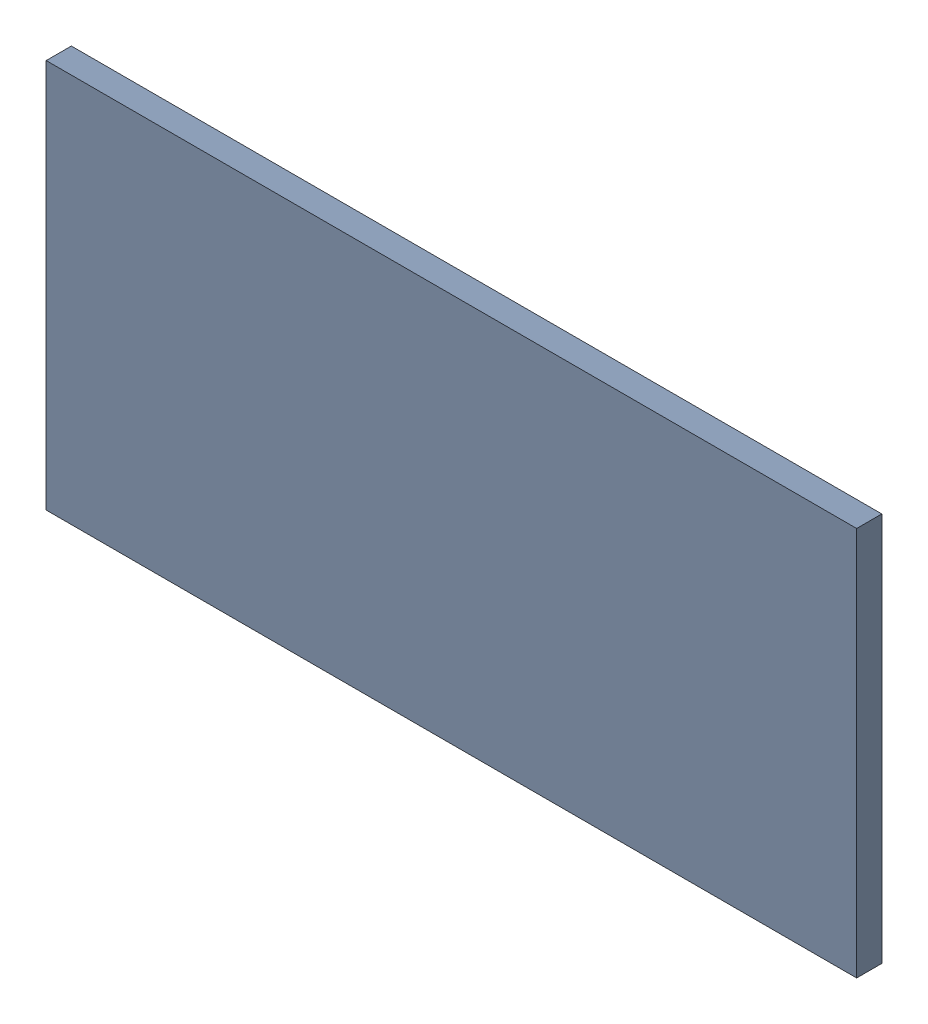
SolidWorks assembly Pad ADXL345-7(18.902mm,57mm) on Top Layer, configuration Predeterminado. Lengths in mm.
Overall size (1.14 0.55 0.04).
2 component instances, 1 part files, 0 mates.
Components (placement in the parent):
- Pad ADXL345-7(18.902mm,57mm) on Top Layer-1-1: Pad ADXL345-7(18.902mm,57mm) on Top Layer-1 [Predeterminado] at (-68.317 -44.187 -0.0457) size (1.14 0.55 0.04)
  - Pad ADXL345-7(18.902mm,57mm) on Top Layer-Part-1-1: Pad ADXL345-7(18.902mm,57mm) on Top Layer-Part-1 [Predeterminado] at origin size (1.14 0.55 0.04)
